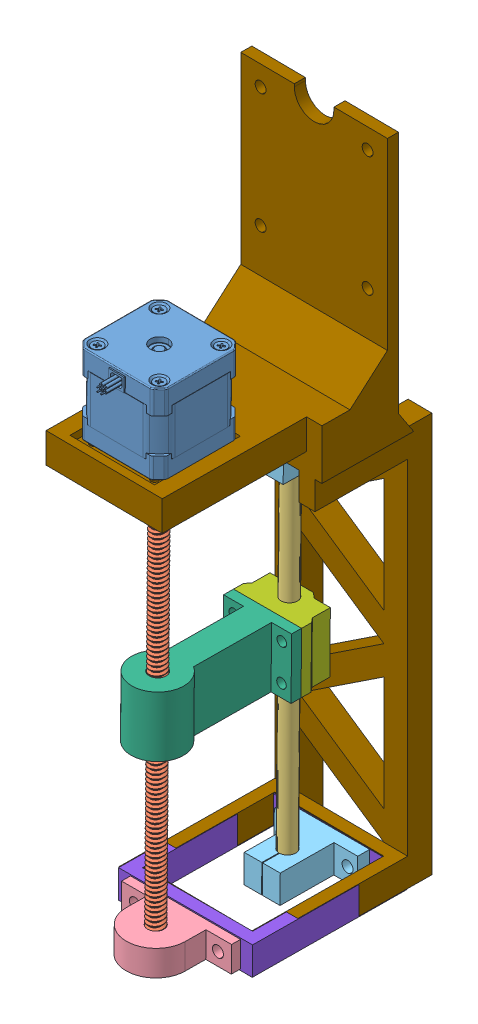
SolidWorks assembly replica, configuration Default. Lengths in mm.
Overall size (75.13 337.75 133.84).
10 component instances, 9 part files, 15 mates.
Components (placement in the parent):
- Nema17-1: Nema17 [Default] at (-45.5926 68.0694 -5.5609) x (-0.999962 0.008727 0) z (0 0 1) size (42.3 62.01 51.35)
- threaded-rod-1: threaded-rod [Default] at (-46.0647 1.3733 -5.843) x (1 0 0) z (0 -0.999962 0.008727) size (8.28 9.24 200.12)
- smooth-rod-1: smooth-rod [Default] at (-46.11 -1.0158 -71.7247) x (1 -0.000006 -0.000688) z (0 -0.999962 0.008727) size (8 8 200)
- threaded-rod-holder-1: threaded-rod-holder [Default] at (-46.0749 -183.0641 -19.134) x (1 -0.000006 -0.000688) z (0 -0.999962 0.008727) size (55 29.61 12.8)
- smooth-rod-holder-1: smooth-rod-holder [Default] at (-46.124 -183.0863 -90.4365) x (1 -0.000006 -0.000688) z (0 -0.999962 0.008727) size (41.7 32.9 14)
- smooth-rod-holder-2: smooth-rod-holder [Default] at (-46.124 -1.5484 -92.0208) x (1 -0.000006 -0.000688) z (0 -0.999962 0.008727) size (41.7 32.9 14)
- cartridge-v001-1: cartridge-v001 [Default] at (-46.1025 -104.0955 -59.9247) x (0.000688 0.008727 0.999962) z (-1 0.000006 0.000688) size (68 30 34)
- linear-bearing-1: linear-bearing [Default] at (-46.1025 -104.0955 -59.9247) x (1 -0.000006 -0.000688) z (0 0.999962 -0.008727) size (34 18.67 30)
- bottom-rectangle-v001-1: bottom-rectangle-v001 [Default] at (-46.1015 -196.8013 -57.7156) x (0.000688 0.008727 0.999962) z (-1 0.000006 0.000688) size (77.4 14 67)
- full-toolhead-v001-1: full-toolhead-v001 [Default] at (-46.238 -196.6647 -58.1842) x (-0.008727 0 0.999962) z (-0.999962 0 -0.008727) size (129.6 333.37 74)
Mates (geometry in assembly coordinates):
- Coincident1: coincident anti-aligned: plane of Nema17-1 through (-45.9417 28.071 -5.5609) normal (-0.008727 -0.999962 0); plane of motor-bracket-v001-1 through (0.5566 27.6652 -30.8609) normal (0.008727 0.999962 0)
- Concentric1: concentric aligned: cylinder of Nema17-1 through (-46.1336 6.0718 -5.5609) axis (0.008727 0.999962 0) radius 2.5; cylinder of motor-bracket-v001-1 through (-46.042 16.5714 -5.5609) axis (0.008727 0.999962 0) radius 11.5
- Parallel1: parallel anti-aligned: plane of Nema17-1 through (-45.9417 28.071 15.4391) normal (0 0 1); plane of motor-bracket-v001-1 through (-67.1909 28.2564 15.7391) normal (0 0 -1)
- Concentric3: concentric aligned: cylinder of threaded-rod-1 through (-46.0647 -198.6191 -4.0977) axis (0 0.999962 -0.008727) radius 4; cylinder of threaded-rod-holder-1 through (-46.0647 -195.7336 -4.1229) axis (0 0.999962 -0.008727) radius 4.1
- Concentric4: concentric aligned: cylinder of smooth-rod-1 through (-46.11 -201.0082 -69.9794) axis (0 0.999962 -0.008727) radius 4; cylinder of smooth-rod-holder-1 through (-46.11 -196.9086 -70.0152) axis (0 0.999962 -0.008727) radius 4.15
- Concentric5: concentric aligned: cylinder of smooth-rod-1 through (-46.11 -201.0082 -69.9794) axis (0 0.999962 -0.008727) radius 4; cylinder of smooth-rod-holder-2 through (-46.11 -15.3707 -71.5994) axis (0 0.999962 -0.008727) radius 4.15
- Concentric6: concentric anti-aligned: cylinder of threaded-rod-1 through (-46.0647 -198.6191 -4.0977) axis (0 0.999962 -0.008727) radius 4; cylinder of cartridge-v001-1 through (-46.0647 -73.6167 -5.1886) axis (0 -0.999962 0.008727) radius 4.25
- Coincident4: coincident anti-aligned: line of cartridge-v001-1 through (-29.1025 -74.0968 -60.1982) axis (-1 0.000006 0.000688); line of linear-bearing-1 through (-63.1025 -74.0966 -60.1748) axis (1 -0.000006 -0.000688)
- Coincident5: coincident aligned: line of cartridge-v001-1 through (-63.1025 -74.0966 -60.1748) axis (0 -0.999962 0.008727); line of linear-bearing-1 through (-63.1025 -74.0966 -60.1748) axis (0 -0.999962 0.008727)
- Concentric7: concentric anti-aligned: cylinder of smooth-rod-1 through (-46.11 -201.0082 -69.9794) axis (0 0.999962 -0.008727) radius 4; cylinder of linear-bearing-1 through (-46.11 -74.1918 -71.0861) axis (0 -0.999962 0.008727) radius 4.1
- Coincident6: coincident anti-aligned: plane of threaded-rod-holder-1 through (-46.0749 -195.8636 -19.0223) normal (-0.000688 -0.008727 -0.999962); plane of bottom-rectangle-v001-1 through (-46.0749 -182.4641 -19.1393) normal (0.000688 0.008727 0.999962)
- Parallel2: parallel anti-aligned: plane of smooth-rod-holder-1 through (-46.124 -197.0858 -90.3144) normal (-0.000688 -0.008727 -0.999962); plane of bottom-rectangle-v001-1 through (-46.124 -183.0872 -90.5365) normal (0.000688 0.008727 0.999962)
- Concentric8: concentric anti-aligned: cylinder of smooth-rod-holder-1 through (-30.2513 -189.799 -57.4876) axis (-0.000688 -0.008727 -0.999962) radius 2.75; cylinder of bottom-rectangle-v001-1 through (-30.2835 -190.2072 -104.264) axis (0.000688 0.008727 0.999962) radius 2.75
- Concentric9: concentric anti-aligned: cylinder of threaded-rod-holder-1 through (-25.3045 -189.2056 10.5156) axis (-0.000688 -0.008727 -0.999962) radius 2.75; cylinder of bottom-rectangle-v001-1 through (-25.3344 -189.5842 -32.8701) axis (0.000688 0.008727 0.999962) radius 2.75
- Parallel3: parallel aligned: plane of threaded-rod-holder-1 through (-46.0749 -183.0641 -19.134) normal (0 0.999962 -0.008727); plane of bottom-rectangle-v001-1 through (-46.1015 -182.8018 -57.8378) normal (0 0.999962 -0.008727)
